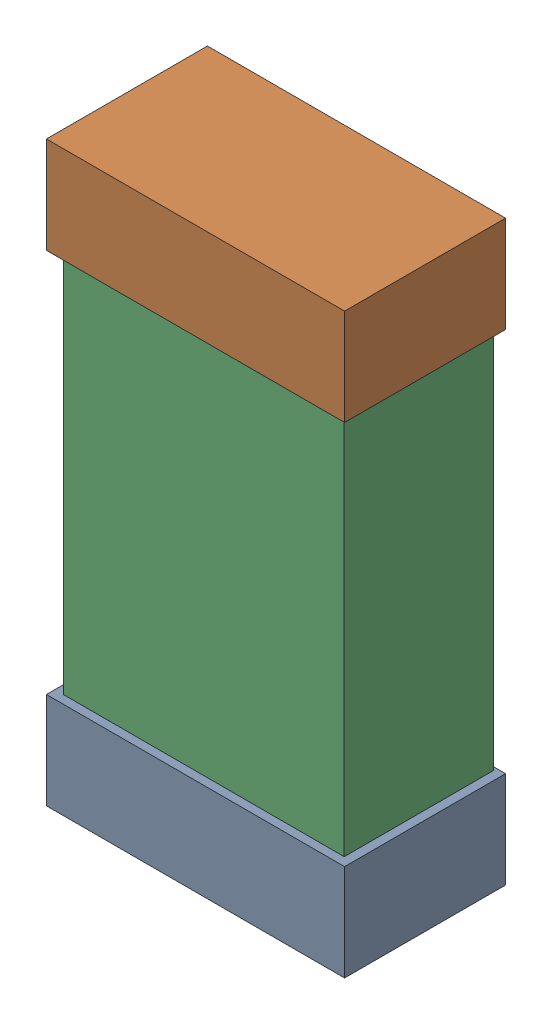
SolidWorks assembly R41, configuration Default. Lengths in mm.
Overall size (0.85 1.65 0.46).
6 component instances, 2 part files, 0 mates.
Components (placement in the parent):
- 432138512_22-1: 432138512_22 [Default] at (9.0999 61.3641 -0.8715) size (0.85 0.28 0.46)
  - Extruded-1: Extruded [Default] at origin size (0.85 0.28 0.46)
- 432138512_23-1: 432138512_23 [Default] at (9.0999 62.7357 -0.8715) size (0.85 0.28 0.46)
  - Extruded-1: Extruded [Default] at origin size (0.85 0.28 0.46)
- 432124816_11-1: 432124816_11 [Default] at (9.0999 62.0499 -0.8615) size (0.8 1.5 0.42)
  - Extruded (1)-1: Extruded (1) [Default] at origin size (0.8 1.5 0.42)
